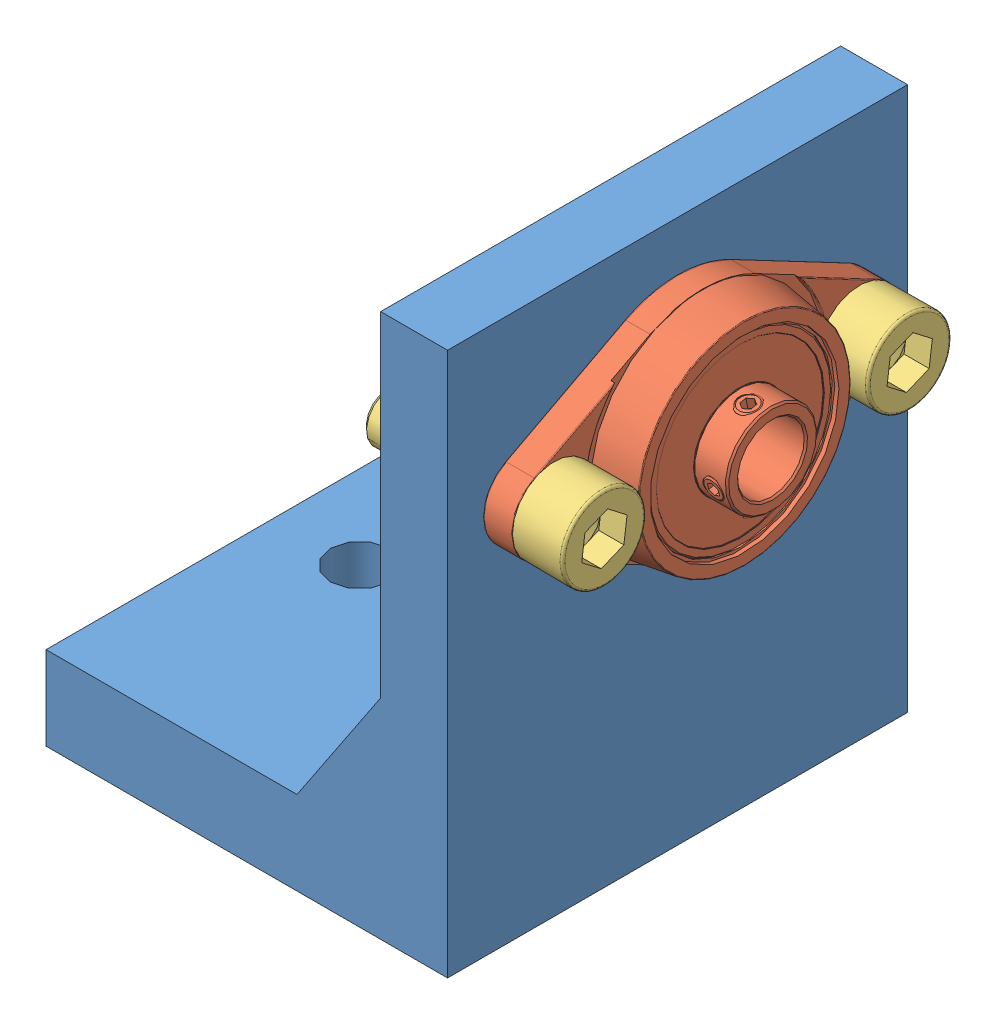
SolidWorks assembly MotorMountBearing, configuration Default. Lengths in mm.
Overall size (59.35 65 55).
6 component instances, 4 part files, 11 mates.
Components (placement in the parent):
- BearingMount-2: BearingMount [Default] at (36.6933 19.0245 31.3737) size (48 65 55)
- KFL08 -1: KFL08  [Default] at (66.7558 66.0878 -15.1263) x (0 -1 0) z (0 0 1) size (28.12 11.35 47.88)
- socket head cap screw_bsi-1: socket head cap screw_bsi [BS EN ISO 4762 M6 x 20 - 20N] at (70.1933 64.6245 13.1237) x (-1 0 0) z (0 -0.924225 -0.381849) size (26 10 10)
- socket head cap screw_bsi-2: socket head cap screw_bsi [BS EN ISO 4762 M6 x 20 - 20N] at (70.1933 64.6245 49.6237) x (-1 0 0) z (0 0.924225 0.381849) size (26 10 10)
- hex flange nut gradea_bsi-1: hex flange nut gradea_bsi [BS EN ISO - 4161 - M5 - N] at (47.6933 64.6245 13.1237) x (0 0 1) z (-1 0 0) size (11.8 11.8 5)
- hex flange nut gradea_bsi-2: hex flange nut gradea_bsi [BS EN ISO - 4161 - M5 - N] at (47.6933 64.6245 49.6237) x (0 0 1) z (-1 0 0) size (11.8 11.8 5)
Mates (geometry in assembly coordinates):
- Coincident1: coincident anti-aligned: line of BearingMount-2 through (52.6933 64.6245 31.3737) axis (1 0 0); line of KFL08 -1 through (68.1933 64.6245 31.3737) axis (-1 0 0)
- Parallel2: parallel anti-aligned: line of BearingMount-2 through (52.6933 64.6245 13.3737) axis (1 0 0); line of KFL08 -1 through (64.1933 64.6245 13.1237) axis (-1 0 0)
- Coincident4: coincident anti-aligned: plane of BearingMount-2 through (60.6933 29.0245 3.8737) normal (1 0 0); plane of KFL08 -1 through (60.6933 78.1853 7.9459) normal (-1 0 0)
- Coincident5: coincident anti-aligned: line of KFL08 -1 through (64.1933 64.6245 49.6237) axis (-1 0 0); line of socket head cap screw_bsi-2 through (44.7478 64.6245 49.6237) axis (1 0 0)
- Coincident6: coincident anti-aligned: plane of KFL08 -1 through (64.1933 73.8925 42.6736) normal (1 0 0); plane of socket head cap screw_bsi-2 through (64.1933 62.7153 54.2449) normal (-1 0 0)
- Coincident7: coincident anti-aligned: line of KFL08 -1 through (64.1933 64.6245 13.1237) axis (-1 0 0); line of socket head cap screw_bsi-1 through (44.7478 64.6245 13.1237) axis (1 0 0)
- Coincident8: coincident anti-aligned: plane of KFL08 -1 through (64.1933 73.8925 8.1531) normal (1 0 0); plane of socket head cap screw_bsi-1 through (64.1933 66.5338 8.5026) normal (-1 0 0)
- Coincident10: coincident anti-aligned: plane of BearingMount-2 through (52.6933 84.0245 3.8737) normal (-1 0 0); plane of hex flange nut gradea_bsi-2 through (52.6933 69.2433 49.6237) normal (1 0 0)
- Coincident11: coincident anti-aligned: plane of BearingMount-2 through (52.6933 84.0245 3.8737) normal (-1 0 0); plane of hex flange nut gradea_bsi-1 through (52.6933 69.2433 13.1237) normal (1 0 0)
- Coincident12: coincident anti-aligned: line of socket head cap screw_bsi-1 through (44.7478 64.6245 13.1237) axis (1 0 0); line of hex flange nut gradea_bsi-1 through (55.5213 64.6245 13.1237) axis (-1 0 0)
- Coincident13: coincident anti-aligned: line of socket head cap screw_bsi-2 through (44.7478 64.6245 49.6237) axis (1 0 0); line of hex flange nut gradea_bsi-2 through (55.5213 64.6245 49.6237) axis (-1 0 0)
